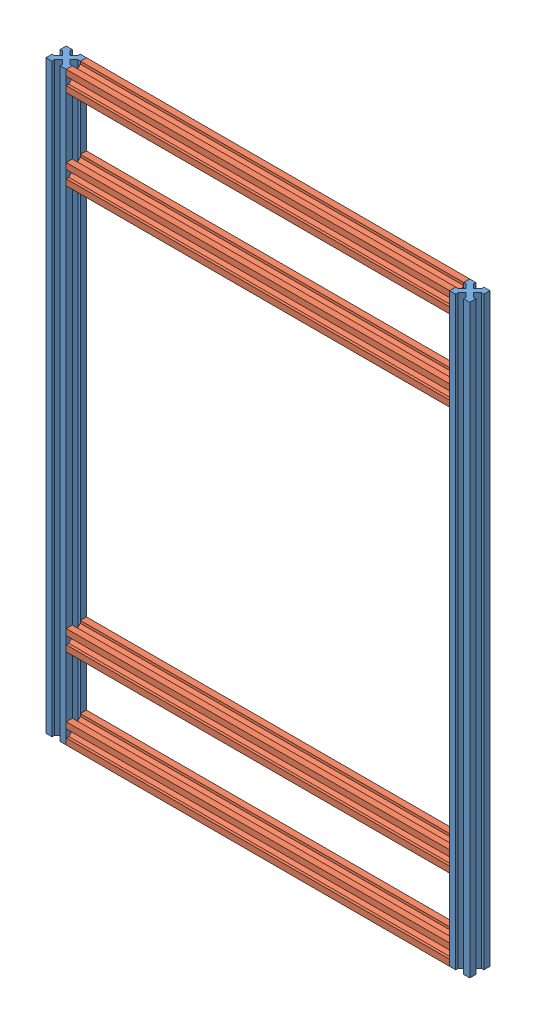
SolidWorks assembly base chassis horizontale, configuration Défaut. Lengths in mm.
Overall size (420 580 20).
6 component instances, 2 part files, 17 mates.
Components (placement in the parent):
- profilé 580-1: profilé 580 [Défaut] at (-152.6624 -292.9685 550) size (20 580 20)
- profilé 380-1: profilé 380 [Défaut] at (-152.6624 -272.9685 550) x (0 0 1) z (0 1 0) size (20 380 20)
- profilé 380-2: profilé 380 [Défaut] at (227.3376 -212.9685 550) x (0 0 1) z (0 -1 0) size (20 380 20)
- profilé 380-3: profilé 380 [Défaut] at (227.3376 267.0315 550) x (0 0 1) z (0 -1 0) size (20 380 20)
- profilé 380-4: profilé 380 [Défaut] at (227.3376 187.0315 550) x (0 0 1) z (0 -1 0) size (20 380 20)
- profilé 580-2: profilé 580 [Défaut] at (247.3376 -292.9685 530) x (0 0 -1) z (1 0 0) size (20 580 20)
Mates (geometry in assembly coordinates):
- Coïncidente1: coincident: point of profilé 540-1; point of profilé 280-1
- Coïncidente3: coincident: point of profilé 540-1; point of profilé 280-1
- Coïncidente4: coincident: line of profilé 540-1 through (-152.6624 287.0315 530) axis (0 -1 0); point of profilé 280-1
- Coïncidente5: coincident: line of profilé 540-1 through (-152.6624 287.0315 530) axis (0 -1 0); point of profilé 280-2
- Coïncidente6: coincident: line of profilé 540-1 through (-152.6624 287.0315 550) axis (0 -1 0); point of profilé 280-2
- Coïncidente7: coincident: line of profilé 540-1 through (-152.6624 287.0315 530) axis (0 -1 0); point of profilé 280-2
- Distance1: distance = 60 mm anti-aligned: plane of profilé 280-1 through (227.3376 -272.9685 550) normal (0 1 0); plane of profilé 280-2 through (-152.6624 -212.9685 550) normal (0 -1 0)
- Coïncidente9: coincident: line of profilé 540-1 through (-152.6624 287.0315 530) axis (0 -1 0); point of profilé 280-3
- Coïncidente10: coincident: line of profilé 540-1 through (-152.6624 287.0315 550) axis (0 -1 0); point of profilé 280-3
- Coïncidente11: coincident: point of profilé 540-1; point of profilé 280-3
- Coïncidente12: coincident: line of profilé 540-1 through (-152.6624 287.0315 530) axis (0 -1 0); point of profilé 280-4
- Coïncidente13: coincident: line of profilé 540-1 through (-152.6624 287.0315 550) axis (0 -1 0); point of profilé 280-4
- Coïncidente14: coincident: line of profilé 540-1 through (-152.6624 287.0315 530) axis (0 -1 0); point of profilé 280-4
- Distance2: distance = 60 mm anti-aligned: plane of profilé 280-3 through (-152.6624 267.0315 550) normal (0 -1 0); plane of profilé 280-4 through (-152.6624 207.0315 550) normal (0 1 0)
- Coïncidente18: coincident: point of profilé 280-3; point of profilé 540-2
- Coïncidente19: coincident: point of profilé 280-3; point of profilé 540-2
- Coïncidente20: coincident: point of profilé 280-3; line of profilé 540-2 through (227.3376 287.0315 530) axis (0 -1 0)
